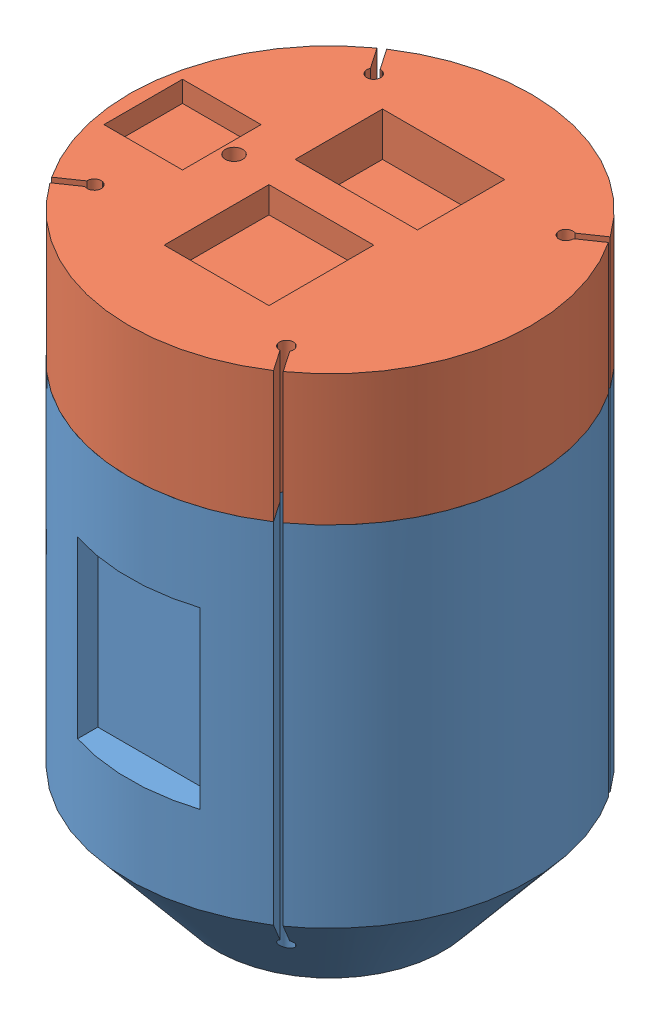
SolidWorks assembly Assieme1, configuration Default. Lengths in mm.
Overall size (230 335 230).
2 component instances, 2 part files, 2 mates.
Components (placement in the parent):
- box_real-1: box_real [Default] at (16.6434 93.3973 0) size (230 260 230)
- tappo_real-1: tappo_real [Default] at (-4.4391 216.1257 0) x (0 0 1) z (0 -1 0) size (230 230 75)
Mates (geometry in assembly coordinates):
- Coincidente2: coincident: circle of box_real-1; circle of tappo_real-1
- Coincidente4: coincident: point of box_real-1; point of tappo_real-1
